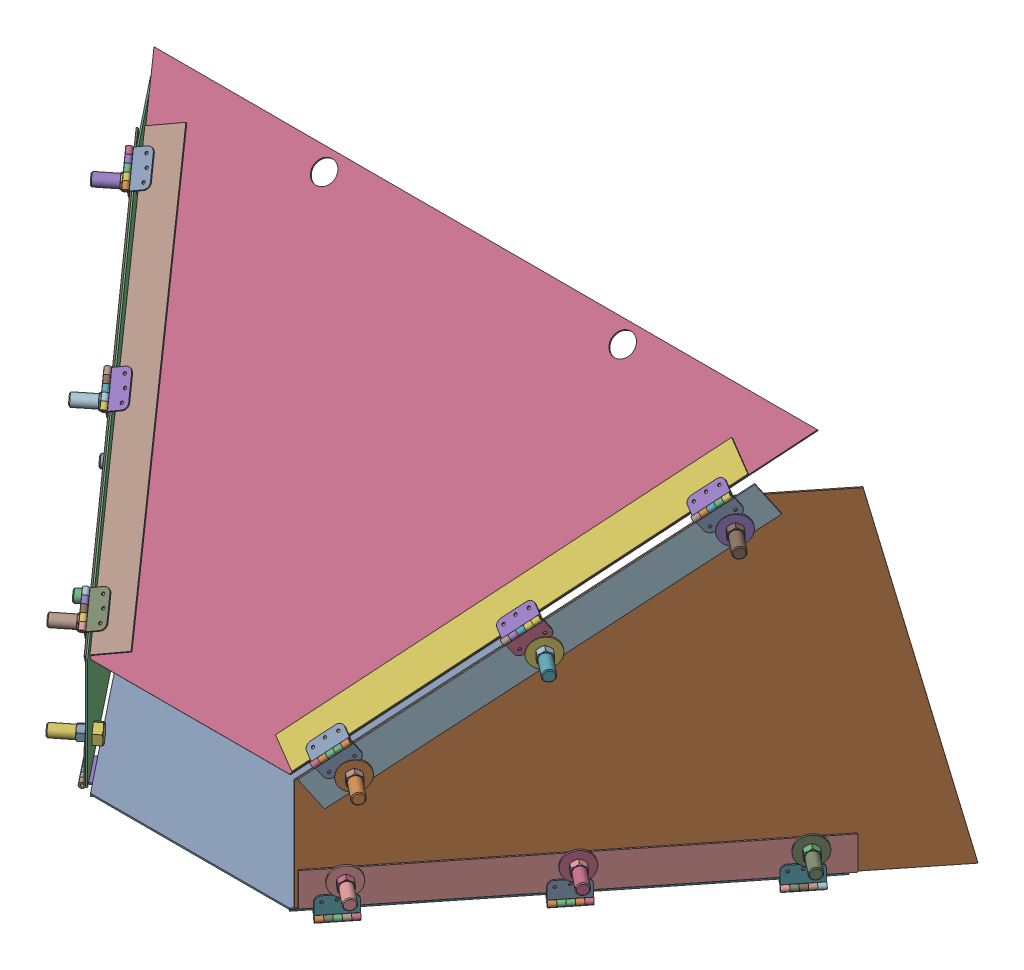
SolidWorks assembly 01-063-00-0(Default), configuration Default. Lengths in mm.
Overall size (1870.83 897.68 876.61).
72 component instances, 10 part files, 0 mates.
Components (placement in the parent):
- hex bolt_ai(PreviewCfg)-1: hex bolt_ai(PreviewCfg) [Default] at (-534.6011 20.4425 -261.2907) x (-0.782601 0 0.622524) z (-0.622524 0 -0.782601) size (93.98 43.99 38.1)
- hex bolt_ai(PreviewCfg)-2: hex bolt_ai(PreviewCfg) [Default] at (497.9424 229.7017 323.947) x (0.782601 0 0.622524) z (-0.622524 0 0.782601) size (93.98 43.99 38.1)
- hex bolt_ai(PreviewCfg)-3: hex bolt_ai(PreviewCfg) [Default] at (-297.4196 20.4425 36.8803) x (-0.782601 0 0.622524) z (-0.622524 0 -0.782601) size (93.98 43.99 38.1)
- hex bolt_ai(PreviewCfg)-4: hex bolt_ai(PreviewCfg) [Default] at (726.291 20.4425 36.8803) x (0.782601 0 0.622524) z (-0.622524 0 0.782601) size (93.98 43.99 38.1)
- hex bolt_ai(PreviewCfg)-5: hex bolt_ai(PreviewCfg) [Default] at (-456.735 668.8506 -163.4019) x (-0.782601 0 0.622524) z (-0.622524 0 -0.782601) size (93.98 43.99 38.1)
- hex bolt_ai(PreviewCfg)-6: hex bolt_ai(PreviewCfg) [Default] at (-60.2381 20.4425 335.0513) x (-0.782601 0 0.622524) z (-0.622524 0 -0.782601) size (93.98 43.99 38.1)
- hex bolt_ai(PreviewCfg)-7: hex bolt_ai(PreviewCfg) [Default] at (691.7744 449.2761 80.2725) x (0.782601 0 0.622524) z (-0.622524 0 0.782601) size (93.98 43.99 38.1)
- hex bolt_ai(PreviewCfg)-8: hex bolt_ai(PreviewCfg) [Default] at (-69.0711 229.7017 323.947) x (-0.782601 0 0.622524) z (-0.622524 0 -0.782601) size (93.98 43.99 38.1)
- hex bolt_ai(PreviewCfg)-9: hex bolt_ai(PreviewCfg) [Default] at (963.4724 20.4425 -261.2907) x (0.782601 0 0.622524) z (-0.622524 0 0.782601) size (93.98 43.99 38.1)
- hex bolt_ai(PreviewCfg)-10: hex bolt_ai(PreviewCfg) [Default] at (489.1095 20.4425 335.0513) x (0.782601 0 0.622524) z (-0.622524 0 0.782601) size (93.98 43.99 38.1)
- hex bolt_ai(PreviewCfg)-11: hex bolt_ai(PreviewCfg) [Default] at (885.6063 668.8506 -163.4019) x (0.782601 0 0.622524) z (-0.622524 0 0.782601) size (93.98 43.99 38.1)
- hex bolt_ai(PreviewCfg)-12: hex bolt_ai(PreviewCfg) [Default] at (-262.903 449.2761 80.2725) x (-0.782601 0 0.622524) z (-0.622524 0 -0.782601) size (93.98 43.99 38.1)
- flat washer type a wide_ai(PreviewCfg)-1: flat washer type a wide_ai(PreviewCfg) [Default] at (-281.7872 449.2761 95.294) x (0.782601 0 -0.622524) z (0.622524 0 0.782601) size (4.19 63.5 63.5)
- flat washer type a wide_ai(PreviewCfg)-2: flat washer type a wide_ai(PreviewCfg) [Default] at (516.8266 229.7017 338.9685) x (-0.782601 0 -0.622524) z (0.622524 0 -0.782601) size (4.19 63.5 63.5)
- flat washer type a wide_ai(PreviewCfg)-3: flat washer type a wide_ai(PreviewCfg) [Default] at (-553.4852 20.4425 -246.2692) x (0.782601 0 -0.622524) z (0.622524 0 0.782601) size (4.19 63.5 63.5)
- flat washer type a wide_ai(PreviewCfg)-4: flat washer type a wide_ai(PreviewCfg) [Default] at (745.1751 20.4425 51.9018) x (-0.782601 0 -0.622524) z (0.622524 0 -0.782601) size (4.19 63.5 63.5)
- flat washer type a wide_ai(PreviewCfg)-5: flat washer type a wide_ai(PreviewCfg) [Default] at (904.4905 668.8506 -148.3804) x (-0.782601 0 -0.622524) z (0.622524 0 -0.782601) size (4.19 63.5 63.5)
- flat washer type a wide_ai(PreviewCfg)-6: flat washer type a wide_ai(PreviewCfg) [Default] at (710.6586 449.2761 95.294) x (-0.782601 0 -0.622524) z (0.622524 0 -0.782601) size (4.19 63.5 63.5)
- flat washer type a wide_ai(PreviewCfg)-7: flat washer type a wide_ai(PreviewCfg) [Default] at (-79.1223 20.4425 350.0728) x (0.782601 0 -0.622524) z (0.622524 0 0.782601) size (4.19 63.5 63.5)
- flat washer type a wide_ai(PreviewCfg)-8: flat washer type a wide_ai(PreviewCfg) [Default] at (-87.9553 229.7017 338.9685) x (0.782601 0 -0.622524) z (0.622524 0 0.782601) size (4.19 63.5 63.5)
- flat washer type a wide_ai(PreviewCfg)-9: flat washer type a wide_ai(PreviewCfg) [Default] at (982.3566 20.4425 -246.2692) x (-0.782601 0 -0.622524) z (0.622524 0 -0.782601) size (4.19 63.5 63.5)
- flat washer type a wide_ai(PreviewCfg)-10: flat washer type a wide_ai(PreviewCfg) [Default] at (507.9936 20.4425 350.0728) x (-0.782601 0 -0.622524) z (0.622524 0 -0.782601) size (4.19 63.5 63.5)
- flat washer type a wide_ai(PreviewCfg)-11: flat washer type a wide_ai(PreviewCfg) [Default] at (-475.6192 668.8506 -148.3804) x (0.782601 0 -0.622524) z (0.622524 0 0.782601) size (4.19 63.5 63.5)
- flat washer type a wide_ai(PreviewCfg)-12: flat washer type a wide_ai(PreviewCfg) [Default] at (-316.3038 20.4425 51.9018) x (0.782601 0 -0.622524) z (0.622524 0 0.782601) size (4.19 63.5 63.5)
- hex nut_ai(PreviewCfg)-1: hex nut_ai(PreviewCfg) [Default] at (-95.6211 20.4425 363.1968) x (0.622524 0 0.782601) z (-0.782601 0 0.622524) size (28.57 33 16.89)
- hex nut_ai(PreviewCfg)-2: hex nut_ai(PreviewCfg) [Default] at (-104.4541 229.7017 352.0925) x (0.622524 0 0.782601) z (-0.782601 0 0.622524) size (28.57 33 16.89)
- hex nut_ai(PreviewCfg)-3: hex nut_ai(PreviewCfg) [Default] at (998.8554 20.4425 -233.1452) x (0.622524 0 -0.782601) z (0.782601 0 0.622524) size (28.57 33 16.89)
- hex nut_ai(PreviewCfg)-4: hex nut_ai(PreviewCfg) [Default] at (524.4924 20.4425 363.1968) x (0.622524 0 -0.782601) z (0.782601 0 0.622524) size (28.57 33 16.89)
- hex nut_ai(PreviewCfg)-5: hex nut_ai(PreviewCfg) [Default] at (-332.8026 20.4425 65.0258) x (0.622524 0 0.782601) z (-0.782601 0 0.622524) size (28.57 33 16.89)
- hex nut_ai(PreviewCfg)-6: hex nut_ai(PreviewCfg) [Default] at (-492.118 668.8506 -135.2564) x (0.622524 0 0.782601) z (-0.782601 0 0.622524) size (28.57 33 16.89)
- hex nut_ai(PreviewCfg)-7: hex nut_ai(PreviewCfg) [Default] at (-298.286 449.2761 108.4181) x (0.622524 0 0.782601) z (-0.782601 0 0.622524) size (28.57 33 16.89)
- hex nut_ai(PreviewCfg)-8: hex nut_ai(PreviewCfg) [Default] at (533.3254 229.7017 352.0925) x (0.622524 0 -0.782601) z (0.782601 0 0.622524) size (28.57 33 16.89)
- hex nut_ai(PreviewCfg)-9: hex nut_ai(PreviewCfg) [Default] at (-569.984 20.4425 -233.1452) x (0.622524 0 0.782601) z (-0.782601 0 0.622524) size (28.57 33 16.89)
- hex nut_ai(PreviewCfg)-10: hex nut_ai(PreviewCfg) [Default] at (761.6739 20.4425 65.0258) x (0.622524 0 -0.782601) z (0.782601 0 0.622524) size (28.57 33 16.89)
- hex nut_ai(PreviewCfg)-11: hex nut_ai(PreviewCfg) [Default] at (920.9893 668.8506 -135.2564) x (0.622524 0 -0.782601) z (0.782601 0 0.622524) size (28.57 33 16.89)
- hex nut_ai(PreviewCfg)-12: hex nut_ai(PreviewCfg) [Default] at (727.1574 449.2761 108.4181) x (0.622524 0 -0.782601) z (0.782601 0 0.622524) size (28.57 33 16.89)
- 01-060-00-0-1: 01-060-00-0 [Default] at (-14.1643 -39.0317 412.7) size (1524 3.17 863.6)
- 01-062-00-0-1: 01-062-00-0 [Default] at (1030.468 731.6425 -316.9525) x (-0.622524 0 0.782601) z (0 1 0) size (1117.6 3.17 762)
- 01-062-00-0-2: 01-062-00-0 [Default] at (-604.0814 731.6425 -314.976) x (0.622524 0 0.782601) z (0 1 0) size (1117.6 3.17 762)
- 01-061-00-0-1: 01-061-00-0 [Default] at (-14.1643 228.3047 410.5746) x (1 0 0) z (0 -0.669415 0.742889) size (1524 3.17 914.4)
- 01-065-00-0-1: 01-065-00-0 [Default] at (-14.1643 -42.2067 412.7) x (0.782601 0 -0.622524) z (0.622524 0 0.782601) size (76.2 3.17 914.4)
- 01-065-00-0-2: 01-065-00-0 [Default] at (380.4153 260.0372 380.1021) x (0.863779 -0.337299 0.37432) z (-0.503871 -0.578227 0.641691) size (76.2 3.17 914.4)
- 01-065-00-0-3: 01-065-00-0 [Default] at (383.4015 -42.2067 365.2637) x (0.782601 0 0.622524) z (-0.622524 0 0.782601) size (76.2 3.17 914.4)
- 01-065-00-0-4: 01-065-00-0 [Default] at (-17.3639 234.3351 408.6252) x (0.863779 0.337299 -0.37432) z (0.503871 -0.578227 0.641691) size (76.2 3.17 914.4)
- 01-064-00-0-1: 01-064-00-0 [Default] at (-29.2012 -30.3575 407.7305) x (0 1 0) z (0.622524 0 0.782601) size (76.2 3.17 914.4)
- 01-064-00-0-2: 01-064-00-0 [Default] at (460.5573 -30.3575 409.707) x (0 1 0) z (-0.622524 0 0.782601) size (76.2 3.17 914.4)
- 01-064-00-0-3: 01-064-00-0 [Default] at (-30.9635 227.3021 410.6153) x (-0.358767 -0.817231 -0.451022) z (0.508745 -0.576311 0.639565) size (76.2 3.17 914.4)
- 01-064-00-0-4: 01-064-00-0 [Default] at (457.3501 227.3021 408.6387) x (0.358767 -0.817231 -0.451022) z (-0.508745 -0.576311 0.639565) size (76.2 3.17 914.4)
- 01-066-00-0-1: 01-066-00-0 [Default] at (713.8743 -42.2067 92.6179) x (-0.782601 0 -0.622524) z (-0.622524 0 0.782601) size (49.95 12.7 76.2)
- 01-066-00-0-2: 01-066-00-0 [Default] at (900.7854 738.203 -145.8031) x (-0.860917 0.340562 -0.377941) z (0.508745 0.576311 -0.639565) size (49.95 12.7 76.2)
- 01-066-00-0-3: 01-066-00-0 [Default] at (-569.6208 -42.2067 -265.1873) x (0.782601 0 -0.622524) z (-0.622524 0 -0.782601) size (49.95 12.7 76.2)
- 01-066-00-0-4: 01-066-00-0 [Default] at (476.6929 -42.2067 390.7889) x (-0.782601 0 -0.622524) z (-0.622524 0 0.782601) size (49.95 12.7 76.2)
- 01-066-00-0-5: 01-066-00-0 [Default] at (-240.1626 475.6731 145.5415) x (0.860917 0.340562 -0.377941) z (0.508745 -0.576311 0.639565) size (49.95 12.7 76.2)
- 01-066-00-0-6: 01-066-00-0 [Default] at (-46.3307 256.0986 389.2159) x (0.860917 0.340562 -0.377941) z (0.508745 -0.576311 0.639565) size (49.95 12.7 76.2)
- 01-066-00-0-7: 01-066-00-0 [Default] at (-433.9946 695.2475 -98.133) x (0.860917 0.340562 -0.377941) z (0.508745 -0.576311 0.639565) size (49.95 12.7 76.2)
- 01-066-00-0-8: 01-066-00-0 [Default] at (706.9534 518.6285 97.8713) x (-0.860917 0.340562 -0.377941) z (0.508745 0.576311 -0.639565) size (49.95 12.7 76.2)
- 01-066-00-0-9: 01-066-00-0 [Default] at (-332.4393 -42.2067 32.9837) x (0.782601 0 -0.622524) z (-0.622524 0 -0.782601) size (49.95 12.7 76.2)
- 01-066-00-0-10: 01-066-00-0 [Default] at (513.1215 299.0541 341.5458) x (-0.860917 0.340562 -0.377941) z (0.508745 0.576311 -0.639565) size (49.95 12.7 76.2)
- 01-066-00-0-11: 01-066-00-0 [Default] at (-95.2578 -42.2067 331.1547) x (0.782601 0 -0.622524) z (-0.622524 0 -0.782601) size (49.95 12.7 76.2)
- 01-066-00-0-12: 01-066-00-0 [Default] at (951.0558 -42.2067 -205.5531) x (-0.782601 0 -0.622524) z (-0.622524 0 0.782601) size (49.95 12.7 76.2)
- 01-067-00-0-1: 01-067-00-0 [Default] at (476.0929 253.4895 390.1765) x (0.358767 -0.817231 -0.451022) z (-0.508745 -0.576311 0.639565) size (49.95 12.7 76.2)
- 01-067-00-0-2: 01-067-00-0 [Default] at (-86.8349 298.3638 340.3769) x (-0.358767 -0.817231 -0.451022) z (-0.508745 0.576311 -0.639565) size (49.95 12.7 76.2)
- 01-067-00-0-3: 01-067-00-0 [Default] at (997.8263 -43.0575 -265.7169) x (0 1 0) z (0.622524 0 -0.782601) size (49.95 12.7 76.2)
- 01-067-00-0-4: 01-067-00-0 [Default] at (-521.5187 -43.0575 -206.0827) x (0 1 0) z (0.622524 0 0.782601) size (49.95 12.7 76.2)
- 01-067-00-0-5: 01-067-00-0 [Default] at (760.6448 -43.0575 32.4541) x (0 1 0) z (0.622524 0 -0.782601) size (49.95 12.7 76.2)
- 01-067-00-0-6: 01-067-00-0 [Default] at (669.9249 473.064 146.5021) x (0.358767 -0.817231 -0.451022) z (-0.508745 -0.576311 0.639565) size (49.95 12.7 76.2)
- 01-067-00-0-7: 01-067-00-0 [Default] at (-47.1557 -43.0575 390.2593) x (0 1 0) z (0.622524 0 0.782601) size (49.95 12.7 76.2)
- 01-067-00-0-8: 01-067-00-0 [Default] at (-280.6669 517.9383 96.7025) x (-0.358767 -0.817231 -0.451022) z (-0.508745 0.576311 -0.639565) size (49.95 12.7 76.2)
- 01-067-00-0-9: 01-067-00-0 [Default] at (863.7568 692.6384 -97.1724) x (0.358767 -0.817231 -0.451022) z (-0.508745 -0.576311 0.639565) size (49.95 12.7 76.2)
- 01-067-00-0-10: 01-067-00-0 [Default] at (-474.4988 737.5127 -146.972) x (-0.358767 -0.817231 -0.451022) z (-0.508745 0.576311 -0.639565) size (49.95 12.7 76.2)
- 01-067-00-0-11: 01-067-00-0 [Default] at (523.4634 -43.0575 330.6251) x (0 1 0) z (0.622524 0 -0.782601) size (49.95 12.7 76.2)
- 01-067-00-0-12: 01-067-00-0 [Default] at (-284.3372 -43.0575 92.0883) x (0 1 0) z (0.622524 0 0.782601) size (49.95 12.7 76.2)
